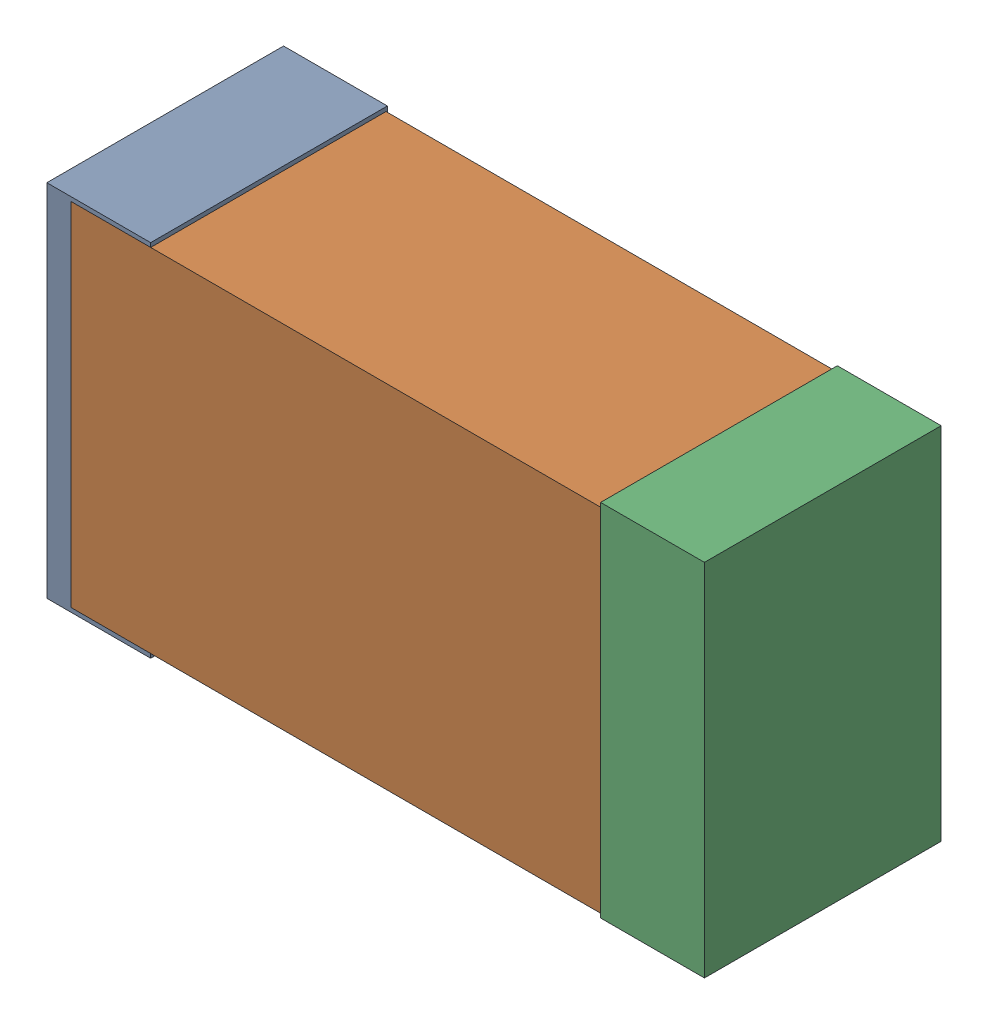
SolidWorks assembly USB67_C10, configuration Default. Lengths in mm.
Overall size (2.38 1.3 0.85).
6 component instances, 2 part files, 0 mates.
Components (placement in the parent):
- 384311232-1: 384311232 [Default] at (150.384 81.28 -1.9574) size (0.38 1.3 0.85)
  - Extruded_8-1: Extruded_8 [Default] at origin size (0.38 1.3 0.85)
- 402662800-1: 402662800 [Default] at (151.384 81.28 -1.9524) size (2.2 1.27 0.85)
  - Extruded_30-1: Extruded_30 [Default] at origin size (2.2 1.27 0.85)
- 384311232-2: 384311232 [Default] at (152.384 81.28 -1.9574) size (0.38 1.3 0.85)
  - Extruded_8-1: Extruded_8 [Default] at origin size (0.38 1.3 0.85)
